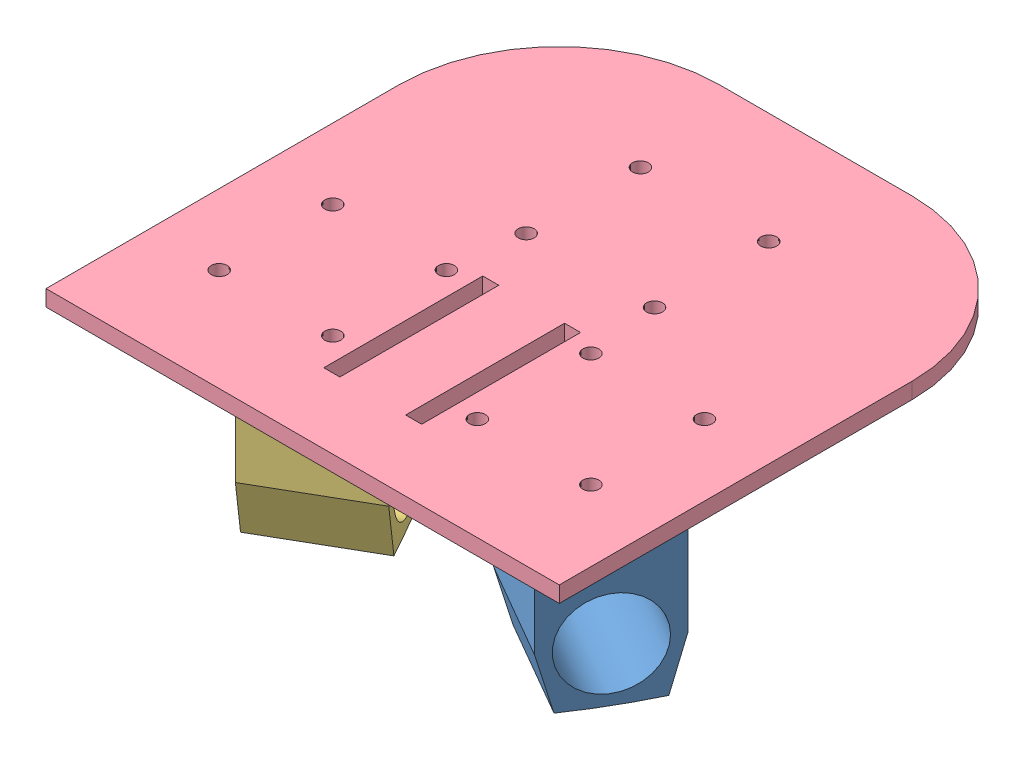
SolidWorks assembly Assem1, configuration Default. Lengths in mm.
Overall size (219.79 83.04 203.2).
4 component instances, 4 part files, 8 mates.
Components (placement in the parent):
- 12V Motor Support - Left-1: 12V Motor Support - Left [Default] at (105.0378 4.8457 6.3728) x (0.866025 0 0.5) z (-0.5 0 0.866025) size (86.05 76.69 86.05)
- 12V Motor Support - Rear-1: 12V Motor Support - Rear [Default] at (54.0063 4.8457 -79.8948) x (0 0 -1) z (1 0 0) size (62.99 76.31 63.5)
- 12V Motor Support -Right-1: 12V Motor Support -Right [Default] at (2.7943 4.8457 6.3728) x (0.866025 0 -0.5) z (0.5 0 0.866025) size (86.05 76.69 86.05)
- Acrylic Plate (square 12 inch) cut version v2 thinner-1: Acrylic Plate (square 12 inch) cut version v2 thinner [Default] at (54.0063 60.2177 -32.145) size (203.2 6.35 203.2)
Mates (geometry in assembly coordinates):
- Coincident1: coincident: plane of 12V Motor Support - Rear-1 through (54.0063 60.2177 -79.8948) normal (0 1 0); plane of Acrylic Plate (square 12 inch) cut version v2 thinner-1 through (54.0063 60.2177 -32.145) normal (0 -1 0)
- Coincident5: coincident: plane of 12V Motor Support - Left-1 through (105.0378 60.2177 6.3728) normal (0 1 0); plane of Acrylic Plate (square 12 inch) cut version v2 thinner-1 through (54.0063 60.2177 -32.145) normal (0 -1 0)
- Concentric6: concentric: circle of 12V Motor Support - Left-1; circle of Acrylic Plate (square 12 inch) cut version v2 thinner-1
- Parallel4: parallel: plane of 12V Motor Support - Left-1 through (73.5418 60.2177 37.8688) normal (-1 0 0); plane of Acrylic Plate (square 12 inch) cut version v2 thinner-1 through (-47.5937 66.5677 69.455) normal (-1 0 0)
- Coincident10: coincident: plane of 12V Motor Support -Right-1 through (2.7943 60.2177 6.3728) normal (0 1 0); plane of Acrylic Plate (square 12 inch) cut version v2 thinner-1 through (54.0063 60.2177 -32.145) normal (0 -1 0)
- Concentric8: concentric: circle of 12V Motor Support -Right-1; circle of Acrylic Plate (square 12 inch) cut version v2 thinner-1
- Parallel5: parallel: plane of 12V Motor Support -Right-1 through (-28.7017 60.2177 37.8688) normal (-1 0 0); plane of Acrylic Plate (square 12 inch) cut version v2 thinner-1 through (-47.5937 66.5677 69.455) normal (-1 0 0)
- Distance1: distance = 69.85 mm: plane of 12V Motor Support - Rear-1 through (22.2563 60.2177 -111.3908) normal (-1 0 0); plane of Acrylic Plate (square 12 inch) cut version v2 thinner-1 through (-47.5937 66.5677 69.455) normal (-1 0 0)
